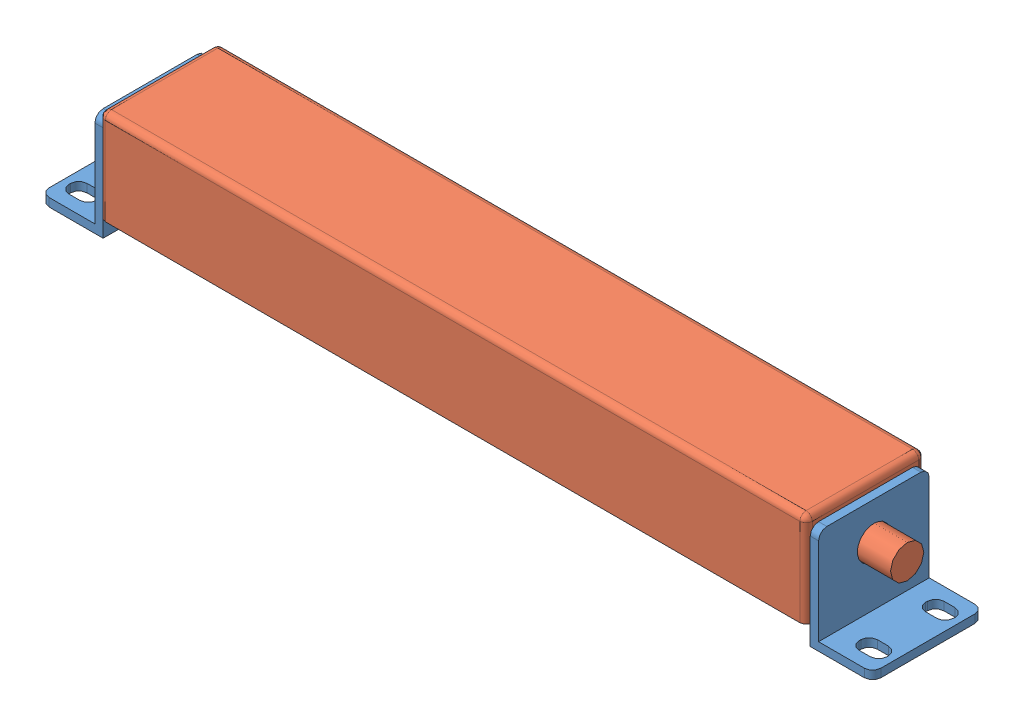
SolidWorks assembly AreaSensor, configuration Default. Lengths in mm.
Overall size (200 27.3 28.6).
3 component instances, 2 part files, 6 mates.
Components (placement in the parent):
- AreaSensorBracket-1: AreaSensorBracket [Default] at (-80.7618 7.8 15.7103) x (0 0 1) z (0 -1 0) size (26.6 15 25)
- AreaSensorBracket-2: AreaSensorBracket [Default] at (89.2382 7.8 15.7103) x (0 0 -1) z (0 -1 0) size (26.6 15 25)
- AreaSensorBW40-04-2: AreaSensorBW40-04 [Default] at (4.2382 0 15.7103) size (185 22.6 28.6)
Mates (geometry in assembly coordinates):
- Coincident3: coincident anti-aligned: plane of AreaSensorBracket-1 through (-80.7618 20.3 2.4103) normal (1 0 0); plane of AreaSensorBW40-04-2 through (-80.7618 22.6 30.0103) normal (-1 0 0)
- Concentric1: concentric anti-aligned: cylinder of AreaSensorBracket-1 through (-80.7618 11.3 15.7103) axis (-1 0 0) radius 4; cylinder of AreaSensorBW40-04-2 through (-85.7618 11.3 15.7103) axis (1 0 0) radius 4
- Parallel1: parallel aligned: plane of AreaSensorBracket-1 through (-82.7618 -4.7 29.0103) normal (0 -1 0); plane of AreaSensorBW40-04-2 through (-80.7618 0 1.4103) normal (0 -1 0)
- Coincident5: coincident: plane of AreaSensorBracket-2 through (89.2382 20.3 29.0103) normal (-1 0 0); plane of AreaSensorBW40-04-2 through (89.2382 22.6 30.0103) normal (1 0 0)
- Concentric2: concentric: cylinder of AreaSensorBracket-2 through (89.2382 11.3 15.7103) axis (1 0 0) radius 4; cylinder of AreaSensorBW40-04-2 through (99.2382 11.3 15.7103) axis (-1 0 0) radius 4
- Parallel2: parallel aligned: plane of AreaSensorBracket-2 through (91.2382 -4.7 2.4103) normal (0 -1 0); plane of AreaSensorBW40-04-2 through (-80.7618 0 1.4103) normal (0 -1 0)
